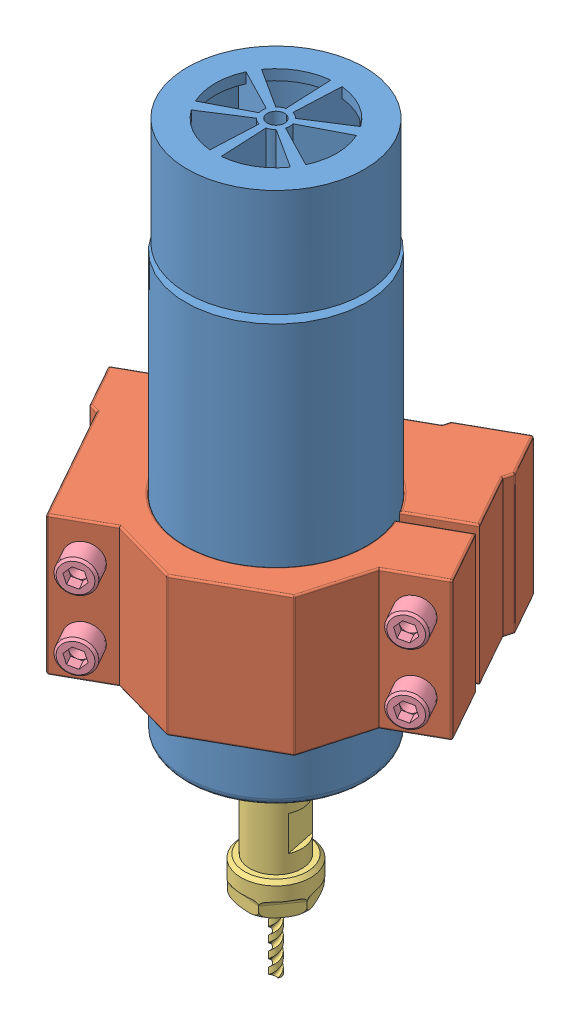
SolidWorks assembly Assemb, configuration По умолчанию. Lengths in mm.
Overall size (112.81 214.81 109.59).
7 component instances, 4 part files, 12 mates.
Components (placement in the parent):
- Spindle-1: Spindle [默认] at (110.2179 160.7098 94.4937) x (1 0 0) z (0 -1 0) size (52 52 178.5)
- Spindle bracket-1: Spindle bracket [По умолчанию] at (132.865 60.2098 42.8399) x (0 1 0) z (0.872476 0 -0.488656) size (40 68 90)
- ER11 Collet-1: ER11 Collet [默认] at (110.2179 10.2098 94.4937) x (-0.978997 0 0.203875) z (-0.203875 0 -0.978997) size (20.08 57.31 20.51)
- socket head cap screw_ai-14: socket head cap screw_ai [HX-SHCS 0.25-28x2.5x2.5-N] at (92.5573 90.2098 134.5864) x (-0.488656 0 -0.872476) z (-0.838381 -0.276821 0.46956) size (69.85 9.53 9.53)
- socket head cap screw_ai-16: socket head cap screw_ai [HX-SHCS 0.25-28x2.5x2.5-N] at (153.6306 90.2098 100.3804) x (-0.488656 0 -0.872476) z (-0.838381 -0.276821 0.46956) size (69.85 9.53 9.53)
- socket head cap screw_ai-17: socket head cap screw_ai [HX-SHCS 0.25-28x2.5x2.5-N] at (92.5573 70.2098 134.5864) x (-0.488656 0 -0.872476) z (-0.838381 -0.276821 0.46956) size (69.85 9.53 9.53)
- socket head cap screw_ai-18: socket head cap screw_ai [HX-SHCS 0.25-28x2.5x2.5-N] at (153.6306 70.2098 100.3804) x (-0.488656 0 -0.872476) z (-0.838381 -0.276821 0.46956) size (69.85 9.53 9.53)
Mates (geometry in assembly coordinates):
- Концентричный1: concentric anti-aligned: cylinder of Spindle-1 through (110.2179 40.2098 94.4937) axis (0 1 0) radius 26; cylinder of Spindle bracket-1 through (110.2179 100.2098 94.4937) axis (0 -1 0) radius 26
- Расстояние1: distance = 20 mm aligned: plane of Spindle-1 through (110.2179 40.2098 94.4937) normal (0 -1 0); plane of Spindle bracket-1 through (132.865 60.2098 42.8399) normal (0 -1 0)
- Расстояние2: distance = 1 mm anti-aligned: plane of ER11 Collet-1 through (110.2179 36.2098 94.4937) normal (0 1 0); plane of Spindle-1 through (110.2179 35.2098 94.4937) normal (0 -1 0)
- Концентричный2: concentric anti-aligned: cylinder of Spindle-1 through (110.2179 15.2098 94.4937) axis (0 1 0) radius 2.5; cylinder of ER11 Collet-1 through (110.2179 36.2098 94.4937) axis (0 -1 0) radius 4
- Концентричный12: concentric anti-aligned: cylinder of Spindle bracket-1 through (96.2955 90.2098 141.2608) axis (-0.488656 0 -0.872476) radius 3.25; cylinder of socket head cap screw_ai-14 through (108.0721 90.2098 162.2875) axis (0.488656 0 0.872476) radius 3.175
- Совпадение12: coincident anti-aligned: plane of Spindle bracket-1 through (82.4745 100.2098 132.9554) normal (0.488656 0 0.872476); plane of socket head cap screw_ai-14 through (90.6046 85.6334 128.4019) normal (-0.488656 0 -0.872476)
- Концентричный13: concentric anti-aligned: cylinder of Spindle bracket-1 through (157.3689 90.2098 107.0549) axis (-0.488656 0 -0.872476) radius 3.25; cylinder of socket head cap screw_ai-16 through (169.1455 90.2098 128.0816) axis (0.488656 0 0.872476) radius 3.175
- Совпадение13: coincident anti-aligned: plane of Spindle bracket-1 through (157.5075 100.2098 90.931) normal (0.488656 0 0.872476); plane of socket head cap screw_ai-16 through (151.6779 85.6334 94.196) normal (-0.488656 0 -0.872476)
- Концентричный14: concentric anti-aligned: cylinder of Spindle bracket-1 through (96.2955 70.2098 141.2608) axis (-0.488656 0 -0.872476) radius 3.25; cylinder of socket head cap screw_ai-17 through (108.0721 70.2098 162.2875) axis (0.488656 0 0.872476) radius 3.175
- Концентричный15: concentric anti-aligned: cylinder of Spindle bracket-1 through (157.3689 70.2098 107.0549) axis (-0.488656 0 -0.872476) radius 3.25; cylinder of socket head cap screw_ai-18 through (169.1455 70.2098 128.0816) axis (0.488656 0 0.872476) radius 3.175
- Совпадение14: coincident anti-aligned: plane of Spindle bracket-1 through (157.5075 100.2098 90.931) normal (0.488656 0 0.872476); plane of socket head cap screw_ai-18 through (151.6779 65.6334 94.196) normal (-0.488656 0 -0.872476)
- Совпадение15: coincident anti-aligned: plane of Spindle bracket-1 through (82.4745 100.2098 132.9554) normal (0.488656 0 0.872476); plane of socket head cap screw_ai-17 through (90.6046 65.6334 128.4019) normal (-0.488656 0 -0.872476)
